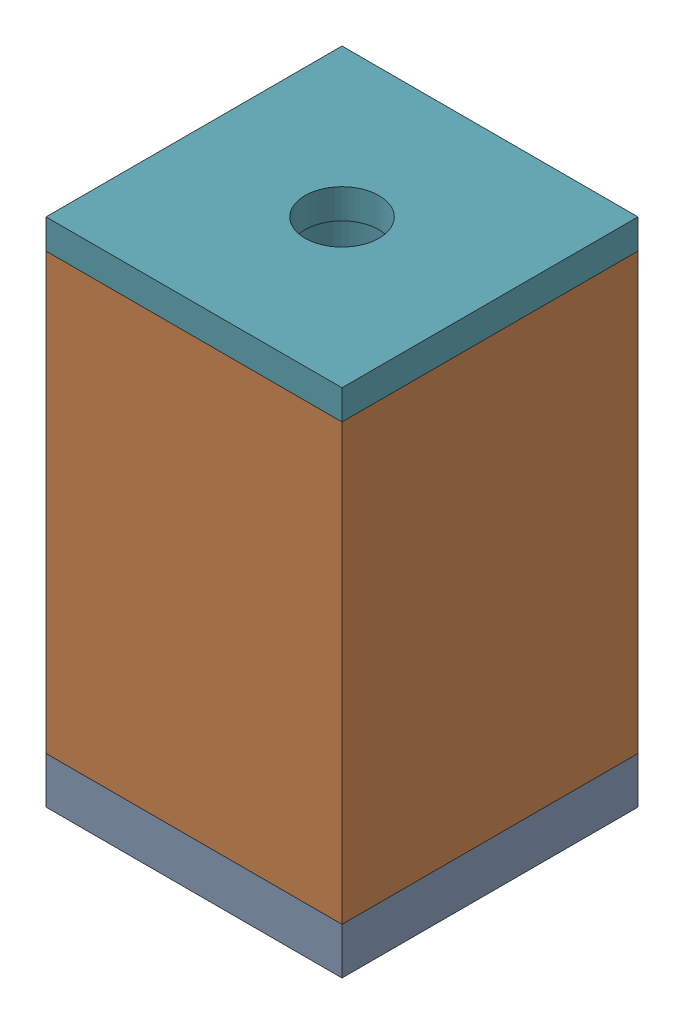
SolidWorks assembly SingleCell, configuration Default. Lengths in mm.
Overall size (11.47 17.27 11.47).
9 component instances, 9 part files, 21 mates.
Components (placement in the parent):
- PCB-1: PCB [Default] at (-4.2697 3.0214 8.3722) size (10 1.57 10)
- Shielding-1: Shielding [Default] at (-4.2697 4.5914 -1.6278) size (10 14.7 10)
- Core_SDR0604-821KL-1: Core_SDR0604-821KL [Default] at (0.7303 4.5914 3.3722) x (-0.775562 0 -0.631272) z (0.631272 0 -0.775562) size (5.8 4.8 5.8)
- Coil_SDR0604-821KL-1: Coil_SDR0604-821KL [Default] at (0.7303 5.3414 3.3722) size (4.9 3.55 4.9)
- Magnet_4mm-1: Magnet_4mm [Default] at (0.7303 10.7524 3.3722) x (0.438483 0 0.898739) z (-0.898739 0 0.438483) size (3 4 3)
- Tactor-1: Tactor [Default] at (0.7303 14.7524 3.3722) x (-0.767194 0 -0.641415) z (0.641415 0 -0.767194) size (1.59 3.17 1.59)
- PTFE_Guide-1: PTFE_Guide [Default] at (5.7303 20.2914 -1.6278) x (-1 0 0) z (0 0 1) size (10 9.53 10)
- Elastomer-1: Elastomer [Default] at (0.7303 9.3914 3.3722) size (6 1.5 6)
- ThermalPad-2: ThermalPad [Default] at (0.7303 4.5914 3.3722) x (0.943532 0 -0.331283) z (0.331283 0 0.943532) size (9 2 9)
Mates (geometry in assembly coordinates):
- Coincident1: coincident aligned: line of PCB-1 through (-4.2697 4.5914 8.3722) axis (0 -1 0); line of Shielding-1 through (-4.2697 19.2914 8.3722) axis (0 -1 0)
- Coincident2: coincident aligned: line of PCB-1 through (-4.2697 4.5914 -1.6278) axis (0 -1 0); line of Shielding-1 through (-4.2697 19.2914 -1.6278) axis (0 -1 0)
- Concentric1: concentric aligned: circle of PCB-1; circle of Core_SDR0604-821KL-1
- Coincident4: coincident anti-aligned: plane of Core_SDR0604-821KL-1 through (0.7303 8.8914 3.3722) normal (0 -1 0); plane of Coil_SDR0604-821KL-1 through (0.7303 8.8914 3.3722) normal (0 1 0)
- Coincident5: coincident aligned: circle of Core_SDR0604-821KL-1; circle of Coil_SDR0604-821KL-1
- Coincident6: coincident anti-aligned: plane of PCB-1 through (-4.2697 4.5914 8.3722) normal (0 1 0); plane of Core_SDR0604-821KL-1 through (0.7303 4.5914 3.3722) normal (0 -1 0)
- Coincident7: coincident anti-aligned: plane of Magnet_4mm-1 through (0.7303 14.7524 3.3722) normal (0 1 0); plane of Tactor-1 through (0.7303 14.7524 3.3722) normal (0 -1 0)
- Concentric2: concentric aligned: circle of Magnet_4mm-1; circle of Tactor-1
- Concentric3: concentric aligned: circle of Core_SDR0604-821KL-1; circle of Tactor-1
- Coincident9: coincident anti-aligned: plane of Shielding-1 through (-4.2697 19.2914 -1.6278) normal (0 1 0); plane of PTFE_Guide-1 through (5.7303 19.2914 -1.6278) normal (0 -1 0)
- Coincident10: coincident anti-aligned: line of Shielding-1 through (-4.2697 19.2914 -1.6278) axis (0 0 1); line of PTFE_Guide-1 through (-4.2697 19.2914 8.3722) axis (0 0 -1)
- Concentric4: concentric anti-aligned: circle of Shielding-1; circle of PTFE_Guide-1
- Concentric5: concentric aligned: circle of Core_SDR0604-821KL-1; circle of HeatSink-1
- Coincident12: coincident aligned: plane of Shielding-1 through (5.7303 19.2914 -1.6278) normal (1 0 0); plane of HeatSink-1 through (5.7303 7.7664 -1.6278) normal (1 0 0)
- Coincident13: coincident anti-aligned: plane of PCB-1 through (-4.2697 4.5914 8.3722) normal (0 1 0); plane of HeatSink-1 through (-4.2697 4.5914 -1.6278) normal (0 -1 0)
- Coincident14: coincident anti-aligned: plane of Shielding-1 through (-4.2697 4.5914 -1.6278) normal (0 -1 0); plane of HeatSink-1 through (-4.2697 7.7664 -1.6278) normal (0 1 0)
- Coincident15: coincident anti-aligned: plane of Core_SDR0604-821KL-1 through (0.7303 9.3914 3.3722) normal (0 1 0); plane of Elastomer-1 through (0.7303 9.3914 3.3722) normal (0 -1 0)
- Concentric6: concentric aligned: circle of Core_SDR0604-821KL-1; circle of Elastomer-1
- Concentric7: concentric aligned: circle of HeatSink-1; circle of ThermalPad-2
- Coincident16: coincident anti-aligned: plane of HeatSink-1 through (-4.2697 6.5914 -1.6278) normal (0 -1 0); plane of ThermalPad-2 through (0.7303 6.5914 3.3722) normal (0 1 0)
- Coincident17: coincident anti-aligned: plane of PCB-1 through (-4.2697 4.5914 8.3722) normal (0 1 0); plane of Shielding-1 through (-4.2697 4.5914 -1.6278) normal (0 -1 0)
